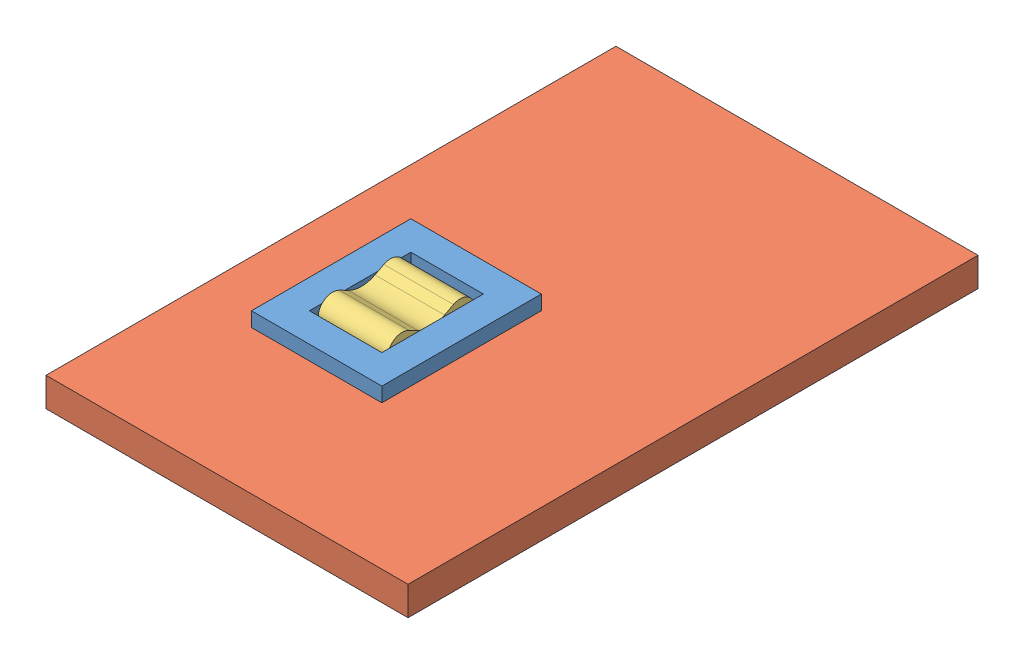
SolidWorks assembly Assem5, configuration Default. Lengths in mm.
Overall size (31.73 6.88 49.95).
4 component instances, 4 part files, 4 mates.
Components (placement in the parent):
- Switch_Housing-1: Switch_Housing [Default] at (-4.7734 5.8688 5.3602) size (11.43 6.35 13.97)
- Part4^Assem5-1: Part4^Assem5 [Default] at origin size (31.73 2.54 49.95) (virtual)
- Switch-1: Switch [Default] at (-4.7734 9.6788 5.3602) size (6.1 4.97 7.62)
- Pin-1: Pin [Default] at (-4.7734 9.6788 5.3602) x (0 -1 0) z (0 0 1) size (1.27 8.89 1.27)
Mates (geometry in assembly coordinates):
- Coincident1: coincident anti-aligned: plane of Switch_Housing-1 through (-4.7734 10.9488 5.3602) normal (0 -1 0); plane of Part4^Assem5-1 through (0 10.9488 0) normal (0 1 0)
- Concentric1: concentric aligned: cylinder of Switch_Housing-1 through (0.9416 9.6788 5.3602) axis (-1 0 0) radius 0.635; cylinder of Switch-1 through (-1.7254 9.6788 5.3602) axis (-1 0 0) radius 0.635
- Width1: width anti-aligned: plane of Switch_Housing-1 through (-7.9484 12.2188 9.8052) normal (1 0 0); plane of Switch_Housing-1 through (-1.5984 12.2188 9.8052) normal (-1 0 0); plane of Switch-1 through (-7.8214 9.6788 5.3602) normal (-1 0 0); plane of Switch-1 through (-1.7254 9.6788 5.3602) normal (1 0 0)
- ProfileCenter1: profile center anti-aligned: circle of Pin-1; circle of Switch_Housing-1
